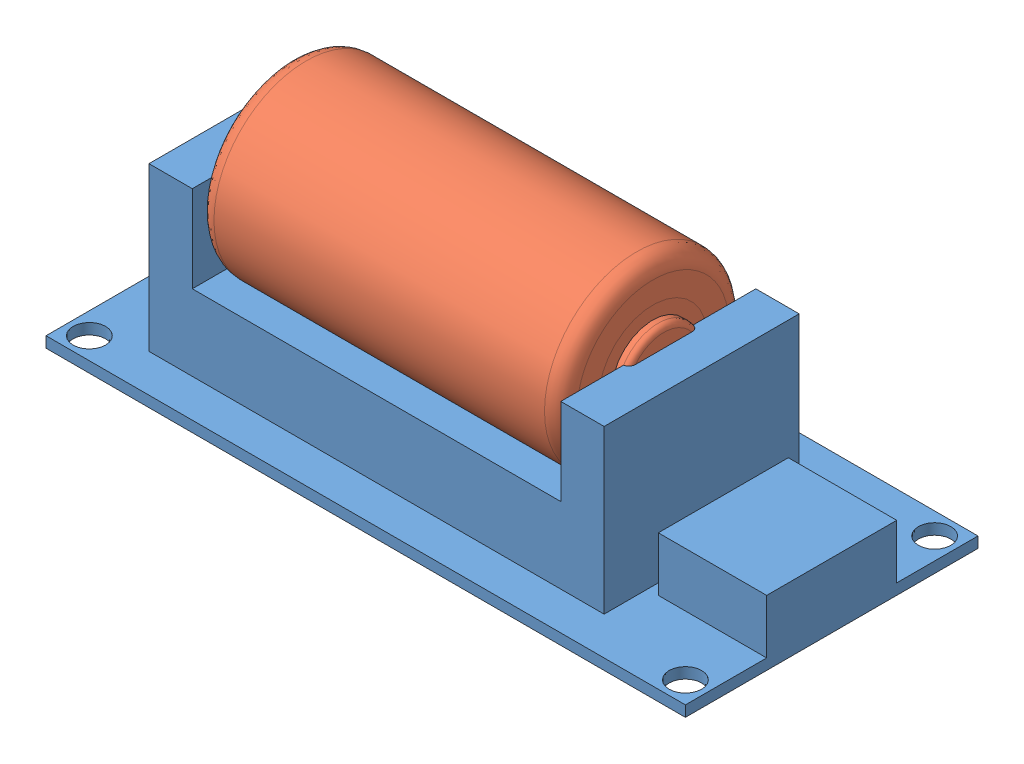
SolidWorks assembly 16340_simple_powerbank, configuration Default. Lengths in mm.
Overall size (59 22.46 27).
2 component instances, 2 part files, 2 mates.
Components (placement in the parent):
- 16340_simple_powerbank-1: 16340_simple_powerbank [Default] at (19.9244 21.3677 52.796) size (59 16 27)
- 16340-1: 16340 [Standard] at (1.7326 35.3281 45.9903) x (0 -1 0) z (0 0 1) size (17 34.5 17)
Mates (geometry in assembly coordinates):
- Coincident1: coincident: plane of 16340_simple_powerbank-1 through (1.7326 37.3677 36.9903) normal (1 0 0); plane of 16340-1 through (1.7326 35.3281 45.9856) normal (-1 0 0)
- Distance1: distance = 0.5 mm: cylinder of 16340-1 through (35.2326 35.3281 45.9903) axis (-1 0 0) radius 8.5; plane of 16340_simple_powerbank-1 through (1.7326 29.3677 54.9903) normal (0 0 1)
